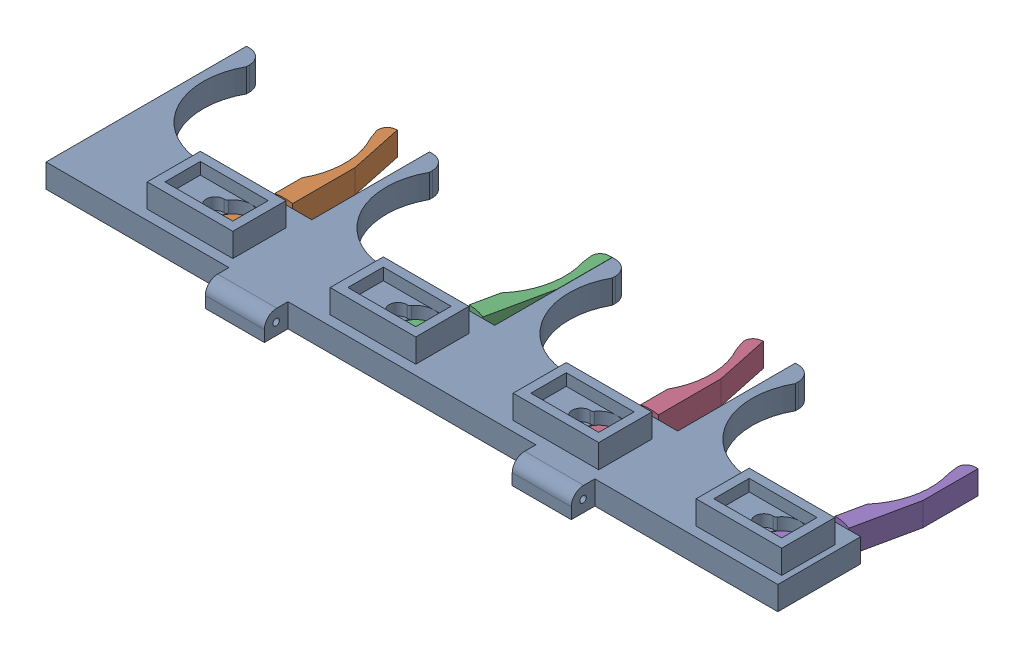
SolidWorks assembly Assemblage_pince multiple, configuration Défaut. Lengths in mm.
Overall size (254.45 16 76.96).
5 component instances, 2 part files, 12 mates.
Components (placement in the parent):
- Pince multiple fixe-1: Pince multiple fixe [Défaut] at (-106.0284 -20.9282 0) size (248 16 75.92)
- Pince mobile-1: Pince mobile [Défaut] at (-55.0284 -20.9282 -12.3046) size (11.6 8 62.46)
- Pince mobile-2: Pince mobile [Défaut] at (6.9716 -20.9282 -12.3046) x (0.978148 0 0.207912) z (-0.207912 0 0.978148) size (11.6 8 62.46)
- Pince mobile-3: Pince mobile [Défaut] at (68.9716 -20.9282 -12.3046) size (11.6 8 62.46)
- Pince mobile-5: Pince mobile [Défaut] at (130.9716 -20.9282 -12.3046) x (0.978148 0 0.207912) z (-0.207912 0 0.978148) size (11.6 8 62.46)
Mates (geometry in assembly coordinates):
- Coaxiale1: concentric aligned: cylinder of Pince multiple fixe-1 through (-55.0284 -12.9282 -12.3046) axis (0 -1 0) radius 6; cylinder of Pince mobile-1 through (-55.0284 -12.9282 -12.3046) axis (0 -1 0) radius 5.8
- Coaxiale2: concentric aligned: cylinder of Pince multiple fixe-1 through (6.9716 -12.9282 -12.3046) axis (0 -1 0) radius 6; cylinder of Pince mobile-2 through (6.9716 -12.9282 -12.3046) axis (0 -1 0) radius 5.8
- Coaxiale3: concentric: cylinder of Pince multiple fixe-1 through (68.9716 -12.9282 -12.3046) axis (0 -1 0) radius 6; cylinder of Pince mobile-3 through (68.9716 -12.9282 -12.3046) axis (0 -1 0) radius 5.8
- Coïncidente1: coincident: plane of Pince multiple fixe-1 through (-105.0284 -20.9282 -62.9235) normal (0 -1 0); plane of Pince mobile-3 through (68.9716 -20.9282 -12.3046) normal (0 -1 0)
- Coïncidente2: coincident aligned: plane of Pince multiple fixe-1 through (-105.0284 -20.9282 -62.9235) normal (0 -1 0); plane of Pince mobile-2 through (6.9716 -20.9282 -12.3046) normal (0 -1 0)
- Coïncidente3: coincident aligned: plane of Pince multiple fixe-1 through (-105.0284 -20.9282 -62.9235) normal (0 -1 0); plane of Pince mobile-1 through (-55.0284 -20.9282 -12.3046) normal (0 -1 0)
- Parallèle3: parallel anti-aligned: plane of Pince multiple fixe-1 through (17.9716 -12.9282 0) normal (-1 0 0); plane of Pince mobile-2 through (17.9031 -12.9282 -67.9042) normal (1 0 0)
- Coaxiale4: concentric aligned: cylinder of Pince multiple fixe-1 through (-79.0284 -12.9282 -50.3046) axis (0 -1 0) radius 24; cylinder of Pince mobile-1 through (-79.0284 -12.9282 -50.3046) axis (0 -1 0) radius 24
- Coaxiale5: concentric: cylinder of Pince multiple fixe-1 through (130.9716 -12.9282 -12.3046) axis (0 -1 0) radius 6; cylinder of Pince mobile-5 through (130.9716 -12.9282 -12.3046) axis (0 -1 0) radius 5.8
- Coïncidente10: coincident: plane of Pince multiple fixe-1 through (-105.0284 -20.9282 -62.9235) normal (0 -1 0); plane of Pince mobile-5 through (130.9716 -20.9282 -12.3046) normal (0 -1 0)
- Parallèle5: parallel aligned: plane of Pince multiple fixe-1 through (141.9716 -12.9282 -28.056) normal (1 0 0); plane of Pince mobile-5 through (141.9031 -12.9282 -67.9042) normal (1 0 0)
- Coaxiale6: concentric aligned: cylinder of Pince multiple fixe-1 through (44.9716 -12.9282 -50.3046) axis (0 -1 0) radius 24; cylinder of Pince mobile-3 through (44.9716 -12.9282 -50.3046) axis (0 -1 0) radius 24
